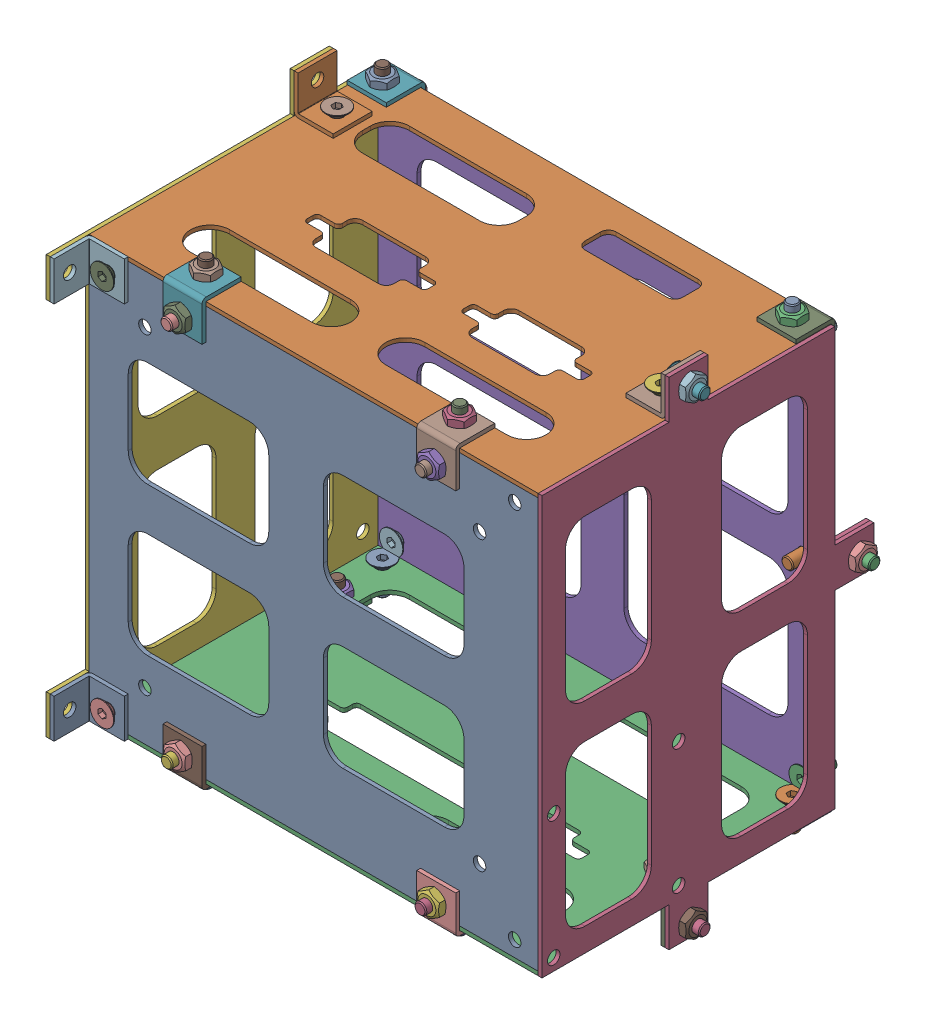
SolidWorks assembly PCB_board_box_reassemb, configuration Default. Lengths in mm.
Overall size (121.33 127 95).
72 component instances, 9 part files, 0 mates.
Components (placement in the parent):
- PCB_board_box_buttom-1: PCB_board_box_buttom [Default] at origin size (115 105 1)
- PCB_board_box_front-1: PCB_board_box_front [Default] at (0 53.5 -36.5) x (0 0 -1) z (0 -1 0) size (75 115 1)
- PCB_board_box_back-1: PCB_board_box_back [Default] at (0 -53.5 -36.5) x (0 0 1) z (0 1 0) size (75 115 1)
- PCB_board_box_right-1: PCB_board_box_right [Default] at (58.5 0 -36.5) x (0 0 1) z (-1 0 0) size (85 127 1)
- PCB_board_box_top-1: PCB_board_box_top [Default] at (0 0 -74) x (0 -1 0) z (0 0 1) size (105 115 1)
- PCB_board_box_left-1: PCB_board_box_left [Default] at (-57.5 0 -36.5) x (0 0 1) z (-1 0 0) size (85 127 1)
- connector_1-1: connector_1 [Default] at (-32.5 49.6 2.1) x (1 0 0) z (0 0 -1) size (10 10 10)
- connector_1-2: connector_1 [Default] at (57.5 58.5 -36.5) x (0 0 1) z (-1 0 0) size (10 10 10)
- connector_1-3: connector_1 [Default] at (57.5 -58.5 -36.5) x (0 0 -1) z (-1 0 0) size (10 10 10)
- connector_1-4: connector_1 [Default] at (32.5 -49.6 2.1) x (-1 0 0) z (0 0 -1) size (10 10 10)
- connector_1-5: connector_1 [Default] at (-32.5 -49.6 2.1) x (-1 0 0) z (0 0 -1) size (10 10 10)
- connector_1-6: connector_1 [Default] at (-57.5 48.5 6) x (0 1 0) z (1 0 0) size (10 10 10)
- connector_1-7: connector_1 [Default] at (-57.5 -48.5 6) x (0 1 0) z (1 0 0) size (10 10 10)
- connector_1-8: connector_1 [Default] at (-57.5 58.5 -56.5) x (0 0 -1) z (1 0 0) size (10 10 10)
- connector_1-9: connector_1 [Default] at (-57.5 -58.5 -56.5) x (0 0 1) z (1 0 0) size (10 10 10)
- connector_1-10: connector_1 [Default] at (52.5 0 -74) x (0 -1 0) z (0 0 -1) size (10 10 10)
- connector_1-11: connector_1 [Default] at (52.5 -49.6 -75.1) size (10 10 10)
- connector_1-12: connector_1 [Default] at (-52.5 -54.6 -70.1) x (-1 0 0) z (0 1 0) size (10 10 10)
- connector_1-13: connector_1 [Default] at (-52.5 49.6 -75.1) x (-1 0 0) z (0 0 1) size (10 10 10)
- connector_1-14: connector_1 [Default] at (32.5 49.6 2.1) x (1 0 0) z (0 0 -1) size (10 10 10)
- connector_1-15: connector_1 [Default] at (52.5 49.6 -75.1) x (-1 0 0) z (0 0 1) size (10 10 10)
- ISO 10642 - M3 x  8-1: ISO 10642 - M3 x  8 [Default] at (-52.5 48.6 -71.3293) x (0 0 -1) z (-1 0 0) size (8 6 6)
- ISO 10642 - M3 x  8-2: ISO 10642 - M3 x  8 [Default] at (-52.5 50.8293 -69.1) x (0 1 0) z (-1 0 0) size (8 6 6)
- ISO 10642 - M3 x  8-3: ISO 10642 - M3 x  8 [Default] at (-52.5 -48.6 -71.3293) x (0 0 -1) z (-1 0 0) size (8 6 6)
- ISO 10642 - M3 x  8-4: ISO 10642 - M3 x  8 [Default] at (-52.5 -50.8293 -69.1) x (0 -1 0) z (-1 0 0) size (8 6 6)
- ISO 10642 - M3 x  8-5: ISO 10642 - M3 x  8 [Default] at (52.5 -50.7586 -69.1) x (0 -1 0) z (-1 0 0) size (8 6 6)
- ISO 10642 - M3 x  8-6: ISO 10642 - M3 x  8 [Default] at (52.5 -48.6 -71.2586) x (0 0 -1) z (-1 0 0) size (8 6 6)
- ISO 10642 - M3 x  8-7: ISO 10642 - M3 x  8 [Default] at (32.5 -48.6 -1.7414) x (0 0 1) z (-1 0 0) size (8 6 6)
- ISO 10642 - M3 x  8-8: ISO 10642 - M3 x  8 [Default] at (32.5 -50.7586 -3.9) x (0 -1 0) z (-1 0 0) size (8 6 6)
- ISO 10642 - M3 x  8-9: ISO 10642 - M3 x  8 [Default] at (-32.5 -48.6 -1.7414) x (0 0 1) z (-1 0 0) size (8 6 6)
- ISO 10642 - M3 x  8-10: ISO 10642 - M3 x  8 [Default] at (-32.5 -50.7586 -3.9) x (0 -1 0) z (-1 0 0) size (8 6 6)
- ISO 10642 - M3 x  8-11: ISO 10642 - M3 x  8 [Default] at (32.5 48.6 -1.7414) x (0 0 1) z (-1 0 0) size (8 6 6)
- ISO 10642 - M3 x  8-12: ISO 10642 - M3 x  8 [Default] at (32.5 50.7586 -3.9) x (0 1 0) z (-1 0 0) size (8 6 6)
- ISO 10642 - M3 x  8-13: ISO 10642 - M3 x  8 [Default] at (-32.5 48.6 -1.6707) x (0 0 1) z (-1 0 0) size (8 6 6)
- ISO 10642 - M3 x  8-14: ISO 10642 - M3 x  8 [Default] at (-32.5 50.7586 -3.9) x (0 1 0) z (-1 0 0) size (8 6 6)
- ISO 10642 - M3 x  8-15: ISO 10642 - M3 x  8 [Default] at (52.5 48.6 -71.2586) x (0 0 -1) z (-1 0 0) size (8 6 6)
- ISO 10642 - M3 x  8-16: ISO 10642 - M3 x  8 [Default] at (52.5 50.7586 -69.1) x (0 1 0) z (-1 0 0) size (8 6 6)
- ISO 10642 - M3 x  8-17: ISO 10642 - M3 x  8 [Default] at (51.5 0 -76.7414) x (0 0 1) z (-1 0 0) size (8 6 6)
- ISO 10642 - M3 x  8-18: ISO 10642 - M3 x  8 [Default] at (54.7586 0 -80) x (1 0 0) z (0 0 -1) size (8 6 6)
- ISO 10642 - M3 x  8-19: ISO 10642 - M3 x  8 [Default] at (54.7586 -59.5 -36.5) x (1 0 0) z (0 0 -1) size (8 6 6)
- ISO 10642 - M3 x  8-20: ISO 10642 - M3 x  8 [Default] at (51.5 -56.2414 -36.5) x (0 1 0) z (-1 0 0) size (8 6 6)
- ISO 10642 - M3 x  8-21: ISO 10642 - M3 x  8 [Default] at (51.5 56.2414 -36.5) x (0 -1 0) z (-1 0 0) size (8 6 6)
- ISO 10642 - M3 x  8-22: ISO 10642 - M3 x  8 [Default] at (54.8293 59.5 -36.5) x (1 0 0) z (0 0 -1) size (8 6 6)
- ISO 10642 - M3 x  8-23: ISO 10642 - M3 x  8 [Default] at (-51.5 56.1707 -56.5) x (0 -1 0) z (-1 0 0) size (8 6 6)
- ISO 10642 - M3 x  8-25: ISO 10642 - M3 x  8 [Default] at (-51.5 48.5 3.7414) x (0 0 -1) z (-1 0 0) size (8 6 6)
- ISO 10642 - M3 x  8-28: ISO 10642 - M3 x  8 [Default] at (-51.5 -48.5 3.7414) x (0 0 -1) z (-1 0 0) size (8 6 6)
- ISO 10642 - M3 x  8-30: ISO 10642 - M3 x  8 [Default] at (-51.5 -56.1707 -56.5) x (0 1 0) z (-1 0 0) size (8 6 6)
- ISO 4032 - M3-1: ISO 4032 - M3 [Default] at (-52.5 48.6 -77.5) x (0 0 1) z (-1 0 0) size (2.4 6.35 5.5)
- ISO 4032 - M3-2: ISO 4032 - M3 [Default] at (-52.5 54.6 -69.1) x (0 1 0) z (-1 0 0) size (2.4 6.35 5.5)
- ISO 4032 - M3-3: ISO 4032 - M3 [Default] at (-51.5 52.5 -56.5) x (0 -1 0) z (-1 0 0) size (2.4 6.35 5.5)
- ISO 4032 - M3-4: ISO 4032 - M3 [Default] at (-52.5 -48.6 -75.1) x (0 0 -1) z (-1 0 0) size (2.4 6.35 5.5)
- ISO 4032 - M3-5: ISO 4032 - M3 [Default] at (-52.5 -54.6 -69.1) x (0 -1 0) z (-1 0 0) size (2.4 6.35 5.5)
- ISO 4032 - M3-6: ISO 4032 - M3 [Default] at (-51.5 -52.5 -56.5) x (0 1 0) z (-1 0 0) size (2.4 6.35 5.5)
- ISO 4032 - M3-7: ISO 4032 - M3 [Default] at (-51.5 -48.5 0) x (0 0 -1) z (-1 0 0) size (2.4 6.35 5.5)
- ISO 4032 - M3-8: ISO 4032 - M3 [Default] at (-51.5 48.5 0) x (0 0 -1) z (-1 0 0) size (2.4 6.35 5.5)
- ISO 4032 - M3-9: ISO 4032 - M3 [Default] at (-32.5 57 -3.9) x (0 -1 0) z (-1 0 0) size (2.4 6.35 5.5)
- ISO 4032 - M3-10: ISO 4032 - M3 [Default] at (-32.5 48.6 4.5) x (0 0 -1) z (-1 0 0) size (2.4 6.35 5.5)
- ISO 4032 - M3-11: ISO 4032 - M3 [Default] at (-32.5 -48.6 2.1) x (0 0 1) z (-1 0 0) size (2.4 6.35 5.5)
- ISO 4032 - M3-12: ISO 4032 - M3 [Default] at (-32.5 -57 -3.9) x (0 1 0) z (-1 0 0) size (2.4 6.35 5.5)
- ISO 4032 - M3-13: ISO 4032 - M3 [Default] at (52.5 -48.6 -75.1) x (0 0 -1) z (-1 0 0) size (2.4 6.35 5.5)
- ISO 4032 - M3-14: ISO 4032 - M3 [Default] at (52.5 -54.6 -69.1) x (0 -1 0) z (-1 0 0) size (2.4 6.35 5.5)
- ISO 4032 - M3-15: ISO 4032 - M3 [Default] at (52.5 48.6 -75.1) x (0 0 -1) z (-1 0 0) size (2.4 6.35 5.5)
- ISO 4032 - M3-16: ISO 4032 - M3 [Default] at (52.5 54.6 -69.1) x (0 1 0) z (-1 0 0) size (2.4 6.35 5.5)
- ISO 4032 - M3-17: ISO 4032 - M3 [Default] at (32.5 57 -3.9) x (0 -1 0) z (-1 0 0) size (2.4 6.35 5.5)
- ISO 4032 - M3-18: ISO 4032 - M3 [Default] at (32.5 48.6 4.5) x (0 0 -1) z (-1 0 0) size (2.4 6.35 5.5)
- ISO 4032 - M3-19: ISO 4032 - M3 [Default] at (32.5 -48.6 4.5) x (0 0 -1) z (-1 0 0) size (2.4 6.35 5.5)
- ISO 4032 - M3-20: ISO 4032 - M3 [Default] at (32.5 -57 -3.9) x (0 1 0) z (-1 0 0) size (2.4 6.35 5.5)
- ISO 4032 - M3-21: ISO 4032 - M3 [Default] at (51.5 -52.5 -36.5) x (0 1 0) z (-1 0 0) size (2.4 6.35 5.5)
- ISO 4032 - M3-22: ISO 4032 - M3 [Default] at (51.5 52.5 -36.5) x (0 -1 0) z (-1 0 0) size (2.4 6.35 5.5)
- ISO 4032 - M3-23: ISO 4032 - M3 [Default] at (58.5 0 -80) size (2.4 6.35 5.5)
- ISO 4032 - M3-24: ISO 4032 - M3 [Default] at (58.5 -59.5 -36.5) size (2.4 6.35 5.5)
- ISO 4032 - M3-25: ISO 4032 - M3 [Default] at (58.5 59.5 -36.5) size (2.4 6.35 5.5)
